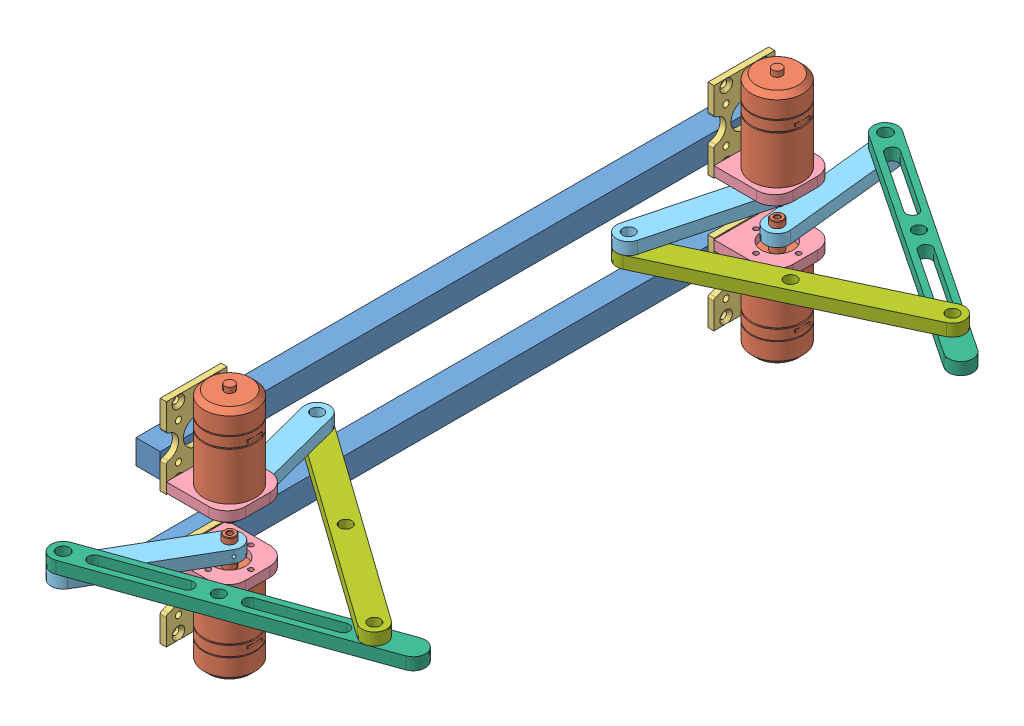
SolidWorks assembly 1, configuration Default. Lengths in mm.
Overall size (254.35 202.8 663.41).
26 component instances, 7 part files, 34 mates.
Components (placement in the parent):
- 盘杆1-1: 盘杆1 [Default] at (246.9831 348.4567 292.4826) size (20 20 500)
- 3508电机-1: 3508电机 [Default] at (208.6146 288.2751 346.5652) x (0 0 -1) z (1 0 0) size (50 96.4 55)
  - RM3508电机-1: RM3508电机 [默认] at (29.0826 29.1816 80.3714) size (42 96.4 42)
  - 电机B盘-1: 电机B盘 [默认] at (54.0826 78.1816 53.3685) x (0 -1 0) z (1 0 0) size (66 5.25 50)
  - 电机C盘-1: 电机C盘 [默认] at (-9.98 77.1816 49.542) x (1 0 0) z (0 -1 0) size (50 50 8)
- 3508电机-2: 3508电机 [Default] at (208.6146 288.2751 796.5652) x (0 0 -1) z (1 0 0) size (50 96.4 55)
  - RM3508电机-1: RM3508电机 [默认] at (29.0826 29.1816 80.3714) size (42 96.4 42)
  - 电机B盘-1: 电机B盘 [默认] at (54.0826 78.1816 53.3685) x (0 -1 0) z (1 0 0) size (66 5.25 50)
  - 电机C盘-1: 电机C盘 [默认] at (-9.98 77.1816 49.542) x (1 0 0) z (0 -1 0) size (50 50 8)
- 10cm-1: 10cm [Default] at (263.8332 377.7567 810.6953) x (-0.503056 0 0.864254) z (0 -1 0) size (120 20 10)
- 20cm-1: 20cm [Default] at (332.8468 387.7567 820.2525) x (0.941664 0 -0.336554) z (0 -1 0) size (245 20 10)
- 10cm-2: 10cm [Default] at (283.723 377.7567 267.7604) x (-0.10526 0 -0.994445) z (0 -1 0) size (120 20 10)
- 20cm-2: 20cm [Default] at (361.5812 377.7567 273.6337) x (0.831212 0 0.555956) z (0 1 0) size (245 20 10)
- 20-1-1: 20-1 [Default] at (427.0132 387.7567 786.5971) x (-0.814765 0 -0.579791) z (0 1 0) size (220 20 10)
- 20-1-2: 20-1 [Default] at (444.7024 397.7567 329.2293) x (-0.905209 0 0.424966) z (0 -1 0) size (220 20 10)
- 10cm-3: 10cm [Default] at (276.5231 407.7567 719.0607) x (-0.249258 0 -0.968437) z (0 -1 0) size (120 20 10)
- 10cm-4: 10cm [Default] at (276.3233 397.7567 365.8526) x (-0.253255 0 0.9674) z (0 1 0) size (120 20 10)
- 3508电机-3: 3508电机 [Default] at (208.6146 487.2383 738.4) x (0 0 1) z (1 0 0) size (50 96.4 55)
  - RM3508电机-1: RM3508电机 [默认] at (29.0826 29.1816 80.3714) size (42 96.4 42)
  - 电机B盘-1: 电机B盘 [默认] at (54.0826 78.1816 53.3685) x (0 -1 0) z (1 0 0) size (66 5.25 50)
  - 电机C盘-1: 电机C盘 [默认] at (-9.98 77.1816 49.542) x (1 0 0) z (0 -1 0) size (50 50 8)
- 3508电机-4: 3508电机 [Default] at (208.6146 487.2383 288.4) x (0 0 1) z (1 0 0) size (50 96.4 55)
  - RM3508电机-1: RM3508电机 [默认] at (29.0826 29.1816 80.3714) size (42 96.4 42)
  - 电机B盘-1: 电机B盘 [默认] at (54.0826 78.1816 53.3685) x (0 -1 0) z (1 0 0) size (66 5.25 50)
  - 电机C盘-1: 电机C盘 [默认] at (-9.98 77.1816 49.542) x (1 0 0) z (0 -1 0) size (50 50 8)
- 盘杆1-2: 盘杆1 [Default] at (246.9831 427.0567 292.4826) size (20 20 500)
Mates (geometry in assembly coordinates):
- 同心2: concentric anti-aligned: cylinder of 3508电机-2/RM3508电机-1 through (288.986 382.7567 767.4826) axis (0 -1 0) radius 5; cylinder of 10cm-1 through (288.986 367.7567 767.4826) axis (0 1 0) radius 5
- 距离1: distance = 5 mm aligned: plane of 10cm-1 through (238.6804 377.7567 853.908) normal (0 1 0); plane of 3508电机-2/RM3508电机-1 through (288.986 382.7567 767.4826) normal (0 1 0)
- 同心5: concentric anti-aligned: cylinder of 10cm-1 through (238.6804 367.7567 853.908) axis (0 1 0) radius 5; circle of 20cm-1
- 重合6: coincident anti-aligned: plane of 10cm-1 through (238.6804 377.7567 853.908) normal (0 1 0); plane of 20cm-1 through (450.5548 377.7567 778.1833) normal (0 -1 0)
- 同心6: concentric anti-aligned: cylinder of 3508电机-1/RM3508电机-1 through (288.986 382.7567 317.4826) axis (0 -1 0) radius 5; cylinder of 10cm-2 through (288.986 367.7567 317.4826) axis (0 1 0) radius 5
- 距离2: distance = 5 mm aligned: plane of 10cm-2 through (278.46 377.7567 218.0381) normal (0 1 0); plane of 3508电机-1/RM3508电机-1 through (288.986 382.7567 317.4826) normal (0 1 0)
- 重合7: coincident anti-aligned: plane of 10cm-2 through (278.46 377.7567 218.0381) normal (0 1 0); plane of 20cm-2 through (465.4827 377.7567 343.1282) normal (0 -1 0)
- 同心7: concentric anti-aligned: cylinder of 10cm-2 through (278.46 367.7567 218.0381) axis (0 1 0) radius 5; cylinder of 20cm-2 through (278.46 387.7567 218.0381) axis (0 -1 0) radius 5.25
- 同心8: concentric anti-aligned: cylinder of 20cm-2 through (444.7024 387.7567 329.2293) axis (0 -1 0) radius 5.25; cylinder of 20-1-2 through (444.7024 387.7567 329.2293) axis (0 1 0) radius 5
- 重合8: coincident anti-aligned: plane of 20cm-2 through (465.4827 387.7567 343.1282) normal (0 1 0); plane of 20-1-2 through (444.7024 387.7567 329.2293) normal (0 -1 0)
- 同心9: concentric anti-aligned: cylinder of 20cm-1 through (427.0132 377.7567 786.5971) axis (0 1 0) radius 5.25; cylinder of 20-1-1 through (427.0132 397.7567 786.5971) axis (0 -1 0) radius 5
- 重合9: coincident anti-aligned: plane of 20cm-1 through (450.5548 387.7567 778.1833) normal (0 1 0); plane of 20-1-1 through (427.0132 387.7567 786.5971) normal (0 -1 0)
- 同心10: concentric anti-aligned: cylinder of 20-1-1 through (264.0602 397.7567 670.6389) axis (0 -1 0) radius 5; cylinder of 10cm-3 through (264.0602 397.7567 670.6389) axis (0 1 0) radius 5
- 重合10: coincident anti-aligned: plane of 20-1-1 through (427.0132 397.7567 786.5971) normal (0 1 0); plane of 10cm-3 through (264.0602 397.7567 670.6389) normal (0 -1 0)
- 同心11: concentric anti-aligned: cylinder of 20-1-2 through (263.6605 387.7567 414.2226) axis (0 1 0) radius 5; cylinder of 10cm-4 through (263.6605 407.7567 414.2226) axis (0 -1 0) radius 5
- 重合11: coincident anti-aligned: plane of 20-1-2 through (444.7024 397.7567 329.2293) normal (0 1 0); plane of 10cm-4 through (263.6605 397.7567 414.2226) normal (0 -1 0)
- 同心12: concentric anti-aligned: cylinder of 3508电机-2/RM3508电机-1 through (288.986 382.7567 767.4826) axis (0 -1 0) radius 5; cylinder of 10cm-3 through (288.986 397.7567 767.4826) axis (0 1 0) radius 5
- 同心13: concentric anti-aligned: cylinder of 10cm-2 through (288.986 367.7567 317.4826) axis (0 1 0) radius 10; cylinder of 10cm-4 through (288.986 407.7567 317.4826) axis (0 -1 0) radius 5
- 同心14: concentric aligned: cylinder of 10cm-3 through (288.986 397.7567 767.4826) axis (0 1 0) radius 5; cylinder of 3508电机-3/RM3508电机-1 through (288.986 392.7567 767.4826) axis (0 1 0) radius 5
- 同心15: concentric anti-aligned: cylinder of 10cm-4 through (288.986 407.7567 317.4826) axis (0 -1 0) radius 5; cylinder of 3508电机-4/RM3508电机-1 through (288.986 392.7567 317.4826) axis (0 1 0) radius 5
- 距离4: distance = 5 mm aligned: plane of 3508电机-4/RM3508电机-1 through (288.986 392.7567 317.4826) normal (0 -1 0); plane of 10cm-4 through (263.6605 397.7567 414.2226) normal (0 -1 0)
- 平行1: parallel aligned: plane of 盘杆1-1 through (256.9831 358.4567 792.4826) normal (1 0 0); plane of 盘杆1-2 through (256.9831 437.0567 792.4826) normal (1 0 0)
- 同心17: concentric aligned: cylinder of 盘杆1-1 through (236.9821 348.4567 332.4826) axis (1 0 0) radius 2.55; cylinder of 3508电机-1/电机B盘-1 through (261.9831 348.4567 332.4826) axis (1 0 0) radius 2.55
- 同心18: concentric aligned: cylinder of 3508电机-4/电机B盘-1 through (261.9831 427.0567 332.4826) axis (1 0 0) radius 2.55; cylinder of 盘杆1-2 through (236.9821 427.0567 332.4826) axis (1 0 0) radius 2.55
- 重合13: coincident anti-aligned: plane of 3508电机-4/电机B盘-1 through (256.9831 409.0567 342.4826) normal (-1 0 0); plane of 盘杆1-2 through (256.9831 437.0567 792.4826) normal (1 0 0)
- 重合14: coincident anti-aligned: plane of 盘杆1-1 through (256.9831 358.4567 792.4826) normal (1 0 0); plane of 3508电机-1/电机B盘-1 through (256.9831 366.4567 292.4826) normal (-1 0 0)
- 同心19: concentric aligned: cylinder of 盘杆1-1 through (236.9821 348.4567 302.4826) axis (1 0 0) radius 2.55; cylinder of 3508电机-1/电机B盘-1 through (261.9831 348.4567 302.4826) axis (1 0 0) radius 2.55
- 同心20: concentric aligned: circle of 3508电机-4/电机B盘-1; cylinder of 盘杆1-2 through (236.9821 427.0567 302.4826) axis (1 0 0) radius 2.55
- 同心21: concentric anti-aligned: cylinder of 3508电机-3/电机B盘-1 through (261.9831 427.0567 782.4826) axis (1 0 0) radius 2.55; circle of 盘杆1-2
- 重合15: coincident anti-aligned: plane of 3508电机-3/电机B盘-1 through (256.9831 409.0567 792.4826) normal (-1 0 0); plane of 盘杆1-2 through (256.9831 437.0567 792.4826) normal (1 0 0)
- 重合16: coincident anti-aligned: plane of 盘杆1-1 through (256.9831 358.4567 792.4826) normal (1 0 0); plane of 3508电机-2/电机B盘-1 through (256.9831 366.4567 742.4826) normal (-1 0 0)
- 同心24: concentric aligned: cylinder of 盘杆1-1 through (236.9821 348.4567 752.4826) axis (1 0 0) radius 2.55; cylinder of 3508电机-2/电机B盘-1 through (261.9831 348.4567 752.4826) axis (1 0 0) radius 2.55
- 平行2: parallel aligned: plane of 3508电机-3/电机B盘-1 through (256.9831 475.0567 792.4826) normal (0 0 1); plane of 盘杆1-2 through (246.9831 427.0567 792.4826) normal (0 0 1)
- 平行3: parallel aligned: plane of 盘杆1-1 through (246.9831 348.4567 792.4826) normal (0 0 1); plane of 3508电机-2/电机B盘-1 through (256.9831 366.4567 792.4826) normal (0 0 1)
